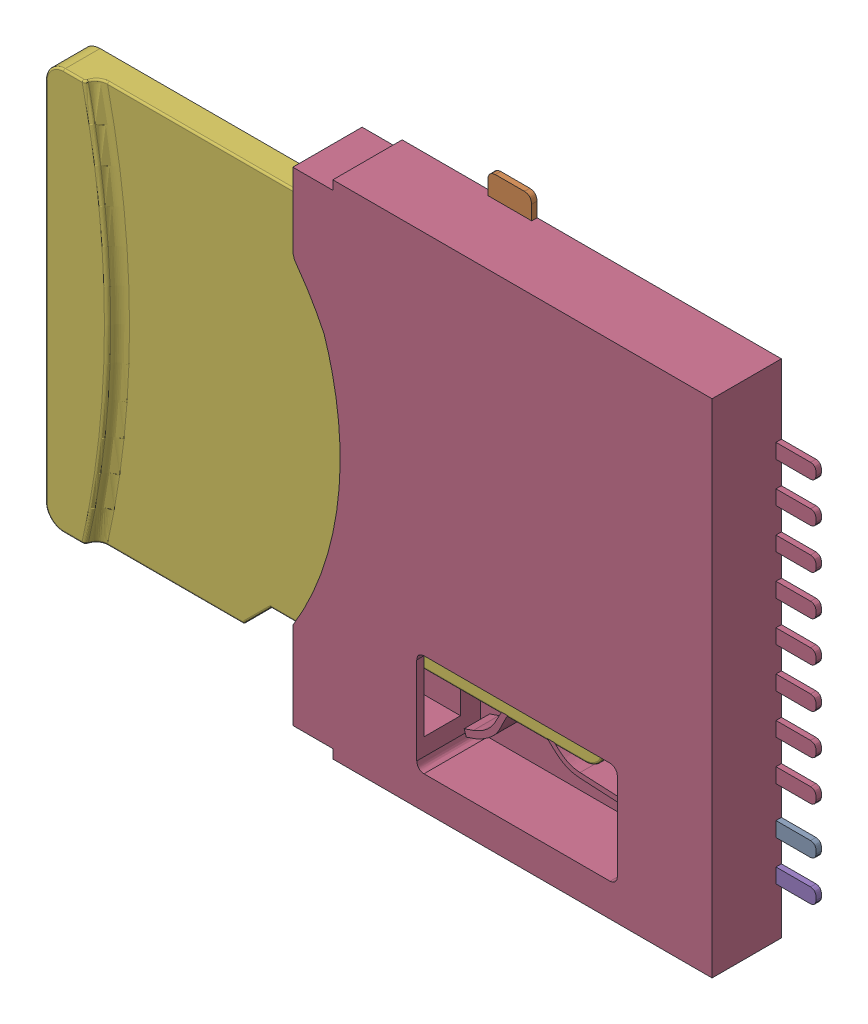
SolidWorks assembly SD SLot Assembly, configuration Default. Lengths in mm.
Overall size (19.43 14.95 2.45).
2 component instances, 2 part files, 0 mates.
Components (placement in the parent):
- SD Slot-1: SD Slot [Default] at (-32.2702 -6.7777 11.7384) size (12.6 14.95 2.45)
- micro_sd_card-1: micro_sd_card [Default] at (-40.6508 -12.1921 12.5884) x (1 0 0) z (0 -1 0) size (15 1.05 11.24)
